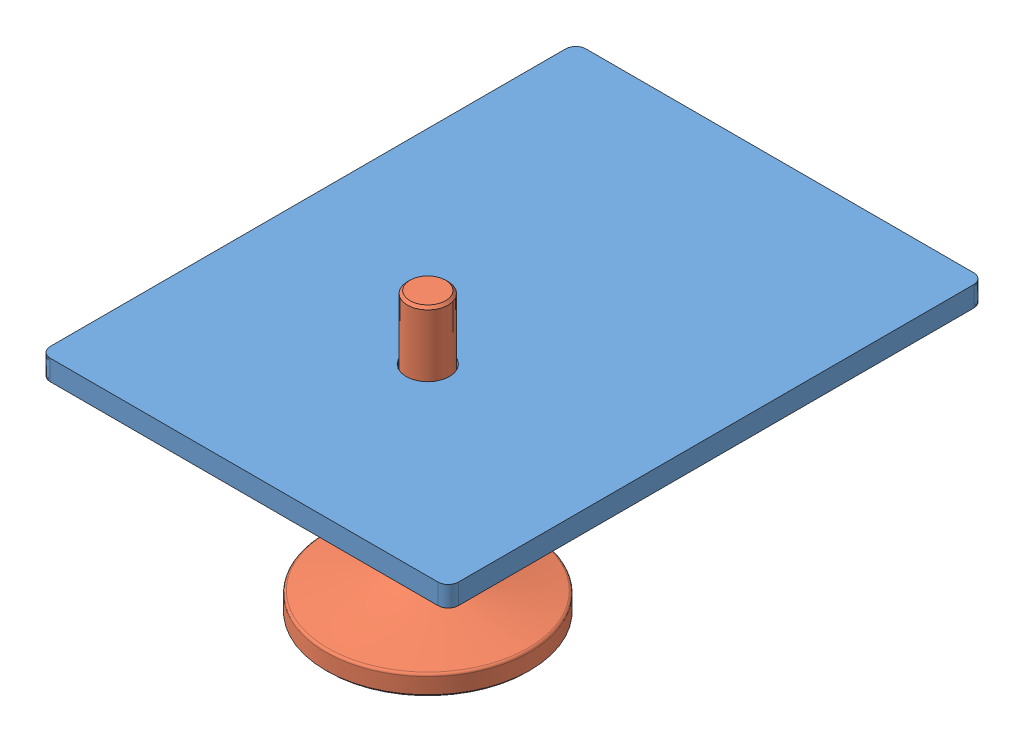
SolidWorks assembly KR.10.12, configuration Default. Lengths in mm.
Overall size (160 110 210).
3 component instances, 3 part files, 6 mates.
Components (placement in the parent):
- KR.12.20-1: KR.12.20 [Default] at origin size (160 8 210)
- EMX_80_1611-1: EMX_80_1611 [Default] at (0 -85 -72) size (80 110 80)
- EP 01 ZKZ 50 F-1: EP 01 ZKZ 50 F [Default] at (0 -44.5 -145) size (92.05 74 50)
Mates (geometry in assembly coordinates):
- Çakışık1: coordinate: point of KR.12.20-1
- Eş Merkezli1: concentric: cylinder of KR.12.20-1 through (0 -10 -72) axis (0 1 0) radius 8.5; cylinder of EMX_80_1611-1 through (0 -70.5873 -72) axis (0 1 0) radius 8
- Uzaklık1: distance = 25 mm aligned: plane of EMX_80_1611-1 through (0 25 -64) normal (0 1 0); plane of KR.12.20-1 through (0 0 0) normal (0 1 0)
- Çakışık2: coincident: plane of KR.12.20-1 through (0 -8 0) normal (0 -1 0); plane of EP 01 ZKZ 50 F-1 through (-19 -8 -147.1707) normal (0 1 0)
- Genişlik1: width: plane of KR.12.20-1 through (-80 -8 -210) normal (-1 0 0); plane of EP 01 ZKZ 50 F-1 through (80 -8 -210) normal (1 0 0); plane of KR.12.20-1 through (25 -8 -147.1707) normal (1 0 0); plane of EP 01 ZKZ 50 F-1 through (-25 -8 -147.1707) normal (-1 0 0)
- Uzaklık2: distance = 40 mm aligned: plane of EP 01 ZKZ 50 F-1 through (-19 -8 -170) normal (0 0 -1); plane of KR.12.20-1 through (-80 -8 -210) normal (0 0 -1)
